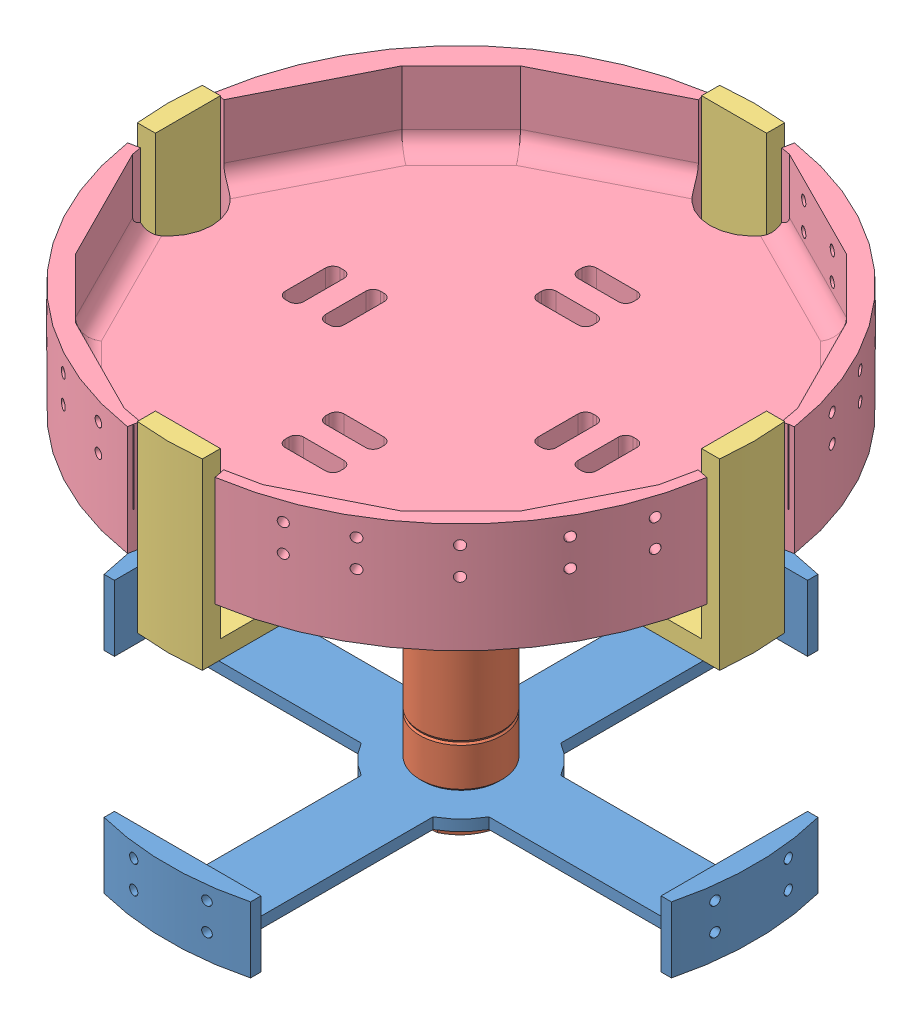
SolidWorks assembly Enclosed_PushPlate_Assembly, configuration Default. Lengths in mm.
Overall size (203.2 162.31 203.2).
4 component instances, 4 part files, 17 mates.
Components (placement in the parent):
- 14022-R01-RECOVERY_SYSTEM_PISTON_MOUNT-1: 14022-R01-RECOVERY_SYSTEM_PISTON_MOUNT [Default] at (-101.6 0 -101.6) x (0 0 1) z (-1 0 0) size (203.2 22.86 203.2)
- 6498K062_ROUND BODY AIR CYLINDER-1: 6498K062_ROUND BODY AIR CYLINDER [6498K062] at (-101.6 45.212 -101.6) x (0 -1 0) z (-0.769 0 -0.639249) size (127.62 28.45 28.45)
- 14021-R01_RECOVERY_SYSTEM_BOTTOM_EJECTION-1: 14021-R01_RECOVERY_SYSTEM_BOTTOM_EJECTION [Default] at (-101.6 86.614 -101.6) size (203.2 63.5 203.2)
- 14020-R01_RECOVERY_SYSTEM_TOP_MOUNT-1: 14020-R01_RECOVERY_SYSTEM_TOP_MOUNT [Default] at (-101.6 108.204 -101.6) x (1 0 0.000188) z (-0.000188 0 1) size (200.91 38.1 200.91)
Mates (geometry in assembly coordinates):
- Coincident1: coincident: plane of 14022-R01-RECOVERY_SYSTEM_PISTON_MOUNT-1 through (-101.6 0 -101.6) normal (0 -1 0); plane of assembly through (0 0 0) normal (0 1 0)
- Concentric1: concentric: circle of 14022-R01-RECOVERY_SYSTEM_PISTON_MOUNT-1; circle of 6498K062_ROUND BODY AIR CYLINDER-1
- Parallel2: parallel: plane of 6498K062_ROUND BODY AIR CYLINDER-1 through (-101.6 -11.938 -101.6) normal (0 -1 0); plane of assembly through (0 0 0) normal (0 1 0)
- Coincident2: coincident: plane of 14022-R01-RECOVERY_SYSTEM_PISTON_MOUNT-1 through (-101.6 3.81 -101.6) normal (0 1 0); circle of 6498K062_ROUND BODY AIR CYLINDER-1
- Parallel3: parallel: plane of 14021-R01_RECOVERY_SYSTEM_BOTTOM_EJECTION-1 through (-101.6 86.614 -101.6) normal (0 -1 0); plane of assembly through (0 0 0) normal (0 1 0)
- Parallel4: parallel: plane of 6498K062_ROUND BODY AIR CYLINDER-1 through (-96.8383 83.439 -88.7028) normal (0 1 0); plane of 14021-R01_RECOVERY_SYSTEM_BOTTOM_EJECTION-1 through (-101.6 86.614 -101.6) normal (0 -1 0)
- Concentric2: concentric: circle of 6498K062_ROUND BODY AIR CYLINDER-1; circle of 14021-R01_RECOVERY_SYSTEM_BOTTOM_EJECTION-1
- Coincident7: coincident: plane of 6498K062_ROUND BODY AIR CYLINDER-1 through (-101.6 86.614 -101.6) normal (0 1 0); plane of 14021-R01_RECOVERY_SYSTEM_BOTTOM_EJECTION-1 through (-101.6 86.614 -101.6) normal (0 -1 0)
- Parallel7: parallel: plane of 14020-R01_RECOVERY_SYSTEM_TOP_MOUNT-1 through (-101.6 108.204 -101.6) normal (0 -1 0); plane of assembly through (0 0 0) normal (0 1 0)
- Tangent11: tangent: cylinder of 14022-R01-RECOVERY_SYSTEM_PISTON_MOUNT-1 through (-101.6 3.81 -101.6) axis (0 -1 0) radius 101.6; plane of assembly through (0 0 0) normal (0 0 1)
- Tangent12: tangent: cylinder of 14022-R01-RECOVERY_SYSTEM_PISTON_MOUNT-1 through (-101.6 3.81 -101.6) axis (0 -1 0) radius 101.6; plane of assembly through (0 0 0) normal (1 0 0)
- Parallel9: parallel: plane of 14021-R01_RECOVERY_SYSTEM_BOTTOM_EJECTION-1 through (-90.3332 150.114 -196.3067) normal (0 0 1); plane of assembly through (0 0 0) normal (0 0 1)
- Distance1: distance = 15.24 mm: plane of 14020-R01_RECOVERY_SYSTEM_TOP_MOUNT-1 through (-101.6 108.204 -101.6) normal (0 -1 0); plane of 14021-R01_RECOVERY_SYSTEM_BOTTOM_EJECTION-1 through (-101.6 92.964 -101.6) normal (0 1 0)
- Distance3: distance = 3.945 mm: line of 14020-R01_RECOVERY_SYSTEM_TOP_MOUNT-1 through (-86.4218 146.304 -1.1401) axis (0 -1 0); line of 14021-R01_RECOVERY_SYSTEM_BOTTOM_EJECTION-1 through (-90.3332 150.114 -0.6266) axis (0 -1 0)
- Parallel10: parallel: plane of 14022-R01-RECOVERY_SYSTEM_PISTON_MOUNT-1 through (-114.0461 3.81 -89.1539) normal (0 0 1); plane of assembly through (0 0 0) normal (0 0 1)
- Parallel11: parallel: plane of 14022-R01-RECOVERY_SYSTEM_PISTON_MOUNT-1 through (-114.0461 3.81 -89.1539) normal (-1 0 0); plane of assembly through (0 0 0) normal (1 0 0)
- Concentric4: concentric: circle of 14022-R01-RECOVERY_SYSTEM_PISTON_MOUNT-1; circle of 14020-R01_RECOVERY_SYSTEM_TOP_MOUNT-1
